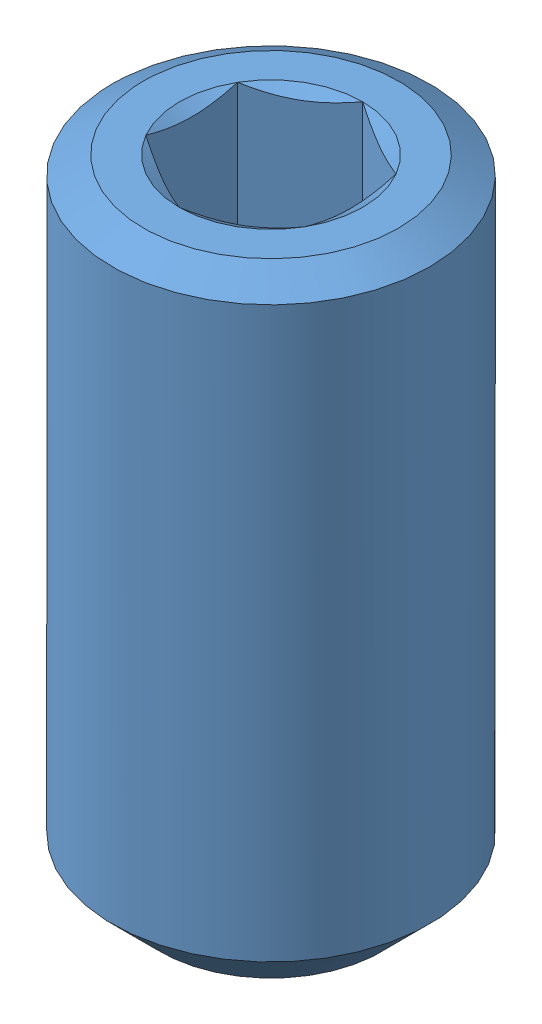
SolidWorks assembly GEABG1_0_45_6_B_8, configuration Default. Lengths in mm.
Overall size (27.5 46.4 46.4).
4 component instances, 3 part files, 0 mates.
Components (placement in the parent):
- GEABP0_8_56_5_B_8-1: GEABP0_8_56_5_B_8 [Default] x (0 0 -1) z (1 0 0) size (46.4 46.4 14)
  - GEABP0_8_56_5_B_8_b-1: GEABP0_8_56_5_B_8_b [Default] x (-1 0 0) z (0 0 -1) size (46.4 46.4 14)
  - Hexagon_socket_set_screw_with_flat_point_DIN_913___M4x3-1: Hexagon_socket_set_screw_with_flat_point_DIN_913___M4x3 [Default] at (0 7 -10) x (0 -1 0) z (1 0 0) size (3 4 4)
- Hexagon_socket_set_screw_with_flat_point_DIN_913___M5x10-1: Hexagon_socket_set_screw_with_flat_point_DIN_913___M5x10 [Default] at (11 14 0) x (0 -1 0) z (0 0 1) size (10.13 5 5)
